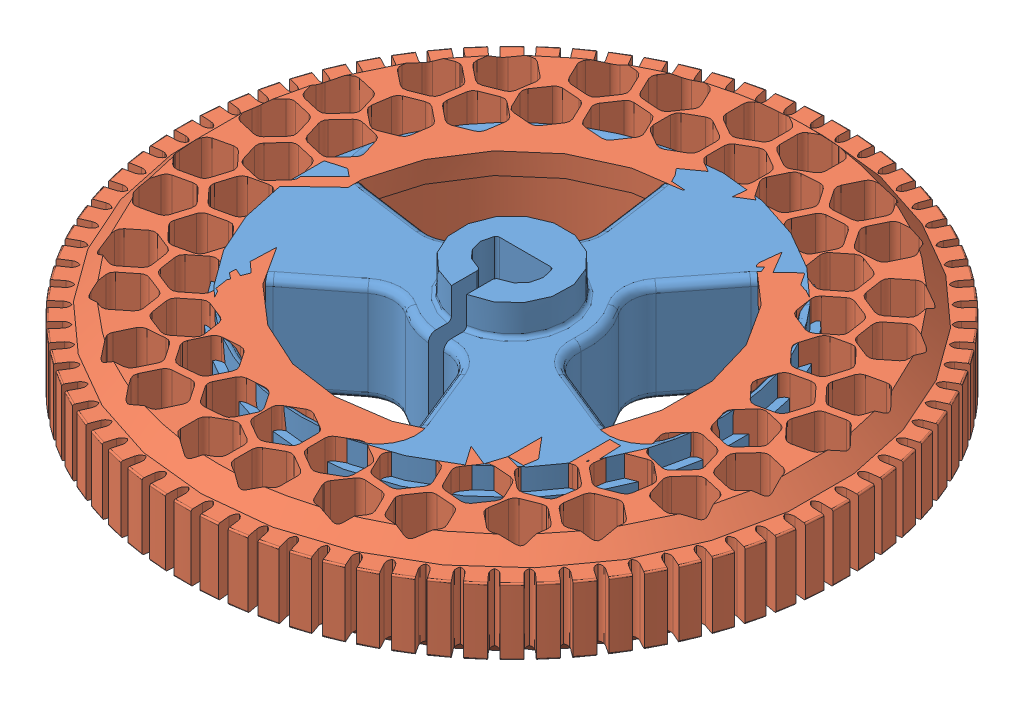
SolidWorks assembly Compression Wheel, configuration Default. Lengths in mm.
Overall size (43.1 8.63 43.1).
2 component instances, 2 part files, 4 mates.
Components (placement in the parent):
- Outer Wheel-1: Outer Wheel [Default] at origin size (28.6 8.63 28.6)
- Part1^Compression Wheel-1: Part1^Compression Wheel [Default] at origin size (43.1 6.6 43.1) (virtual)
Mates (geometry in assembly coordinates):
- InPlace1: in place: plane of ? through (0 0 0) normal (0 0 1); moOrthogonalPlaneRef_w of ? through (0 0 0) normal (0 1 0); plane of ? through (0 0 0) normal (1 0 0); unknown of ?
- Coincident1: coincident aligned: 
- Coincident2: coincident aligned: plane of Part1^Compression Wheel-1 through (0 0 0) normal (0 1 0)
- Coincident3: coincident anti-aligned: plane of Part1^Compression Wheel-1 through (0 0 0) normal (1 0 0)
